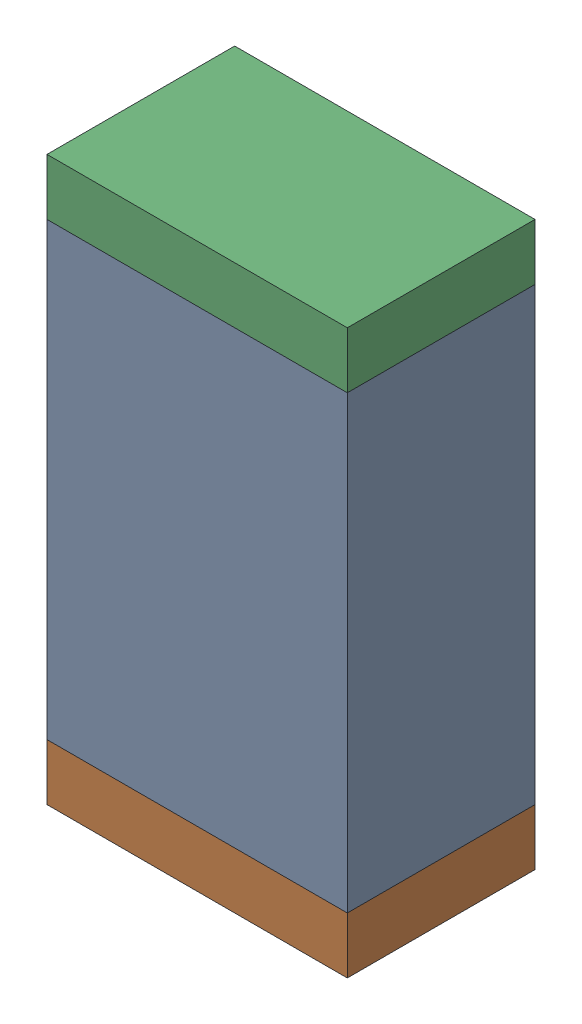
SolidWorks assembly C63, configuration Default. Lengths in mm.
Overall size (0.8 1.5 0.5).
6 component instances, 2 part files, 0 mates.
Components (placement in the parent):
- 810156976-1: 810156976 [Default] at (110.65 55.1 0) size (0.8 1.2 0.5)
  - Extruded_6-1: Extruded_6 [Default] at origin size (0.8 1.2 0.5)
- 810156592-1: 810156592 [Default] at (110.65 54.425 0) size (0.8 0.15 0.5)
  - Extruded_7-1: Extruded_7 [Default] at origin size (0.8 0.15 0.5)
- 810156592-2: 810156592 [Default] at (110.65 55.775 0) size (0.8 0.15 0.5)
  - Extruded_7-1: Extruded_7 [Default] at origin size (0.8 0.15 0.5)
